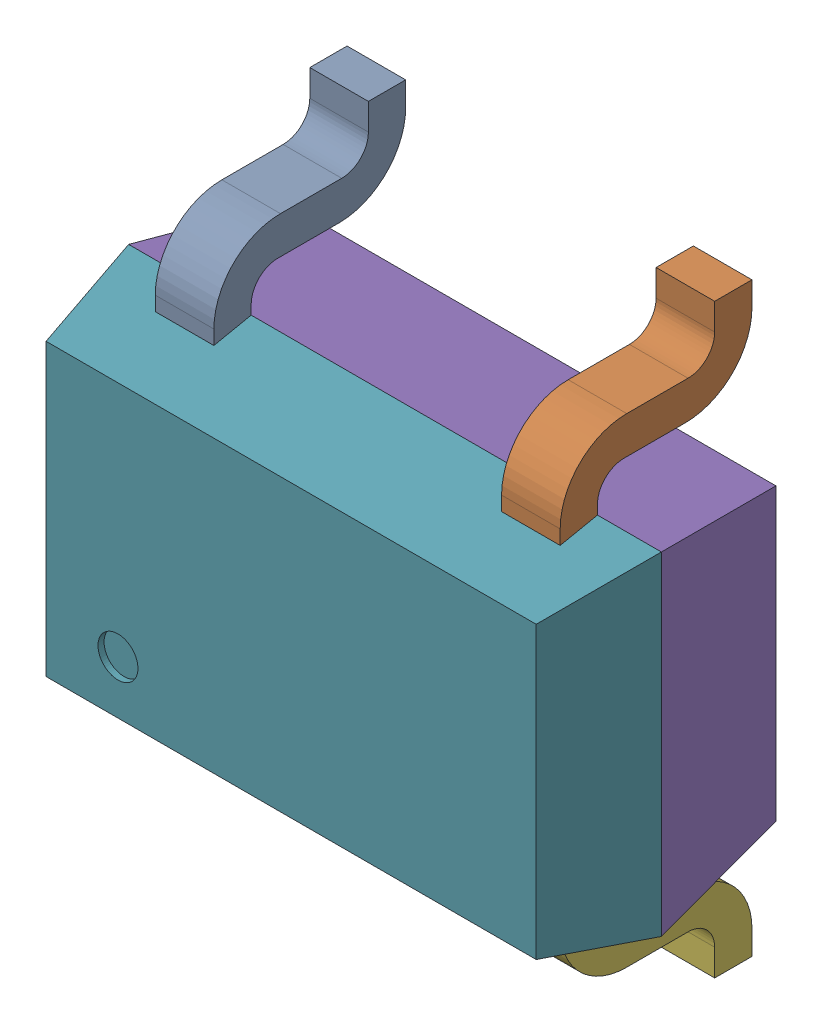
SolidWorks assembly U25.step, configuration Default. Lengths in mm.
Overall size (2 2.2 0.97).
8 component instances, 7 part files, 0 mates.
Components (placement in the parent):
- User Library-SC70-5.step-1: User Library-SC70-5.step [Default] at (24.5109 -21.3359 0.4826) x (1 0 0) z (0 -1 0) size (2 0.97 2.2)
  - User Library-SC70-5_6_1.step-1: User Library-SC70-5_6_1.step [Default] at origin size (0.22 0.72 0.56)
  - User Library-SC70-5_5_1.step-1: User Library-SC70-5_5_1.step [Default] at origin size (0.22 0.72 0.56)
  - User Library-SC70-5_2_1.step-1: User Library-SC70-5_2_1.step [Default] at origin size (0.22 0.72 0.56)
  - User Library-SC70-5_4_1.step-1: User Library-SC70-5_4_1.step [Default] at origin size (0.22 0.72 0.56)
  - User Library-SC70-5_1_1.step-1: User Library-SC70-5_1_1.step [Default] at origin size (2 0.51 1.25)
  - User Library-SC70-5_3_1.step-1: User Library-SC70-5_3_1.step [Default] at origin size (0.22 0.72 0.56)
  - User Library-SC70-5_7_1.step-1: User Library-SC70-5_7_1.step [Default] at origin size (2 0.39 1.25)
